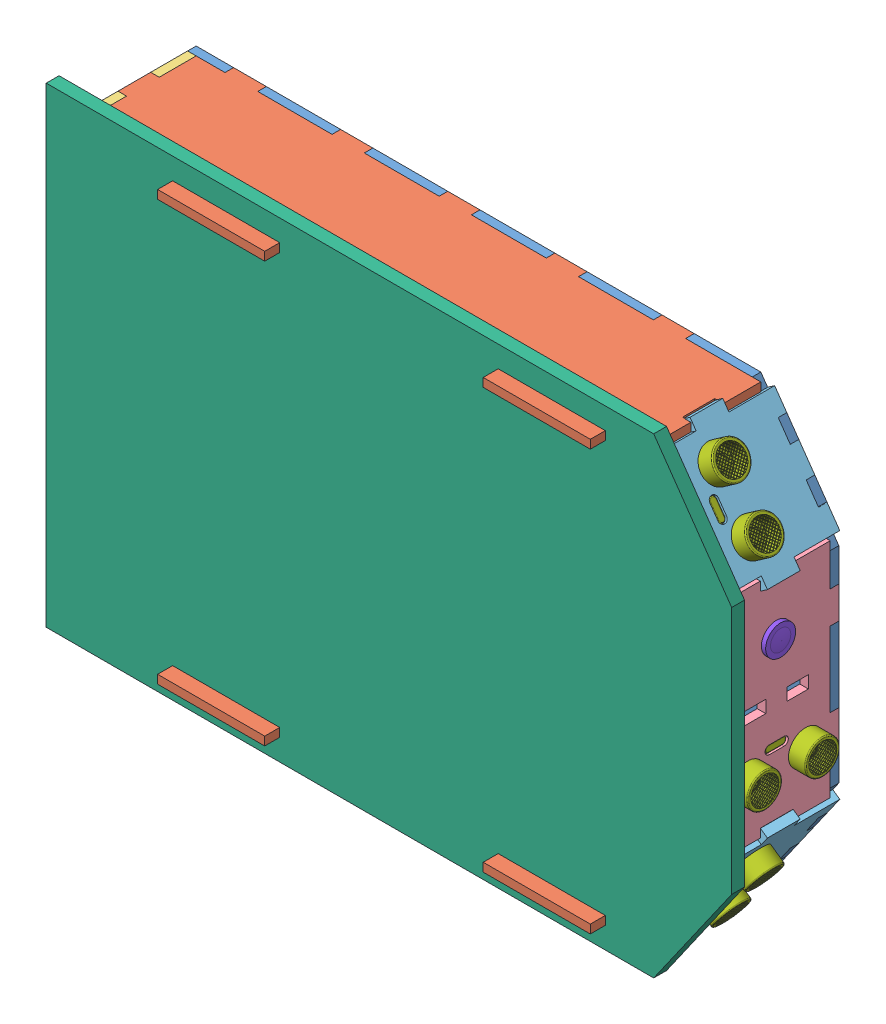
SolidWorks assembly Gehäuse, configuration Standard. Lengths in mm.
Overall size (320 220 121.67).
12 component instances, 8 part files, 34 mates.
Components (placement in the parent):
- Gehäuseunterteil-1: Gehäuseunterteil [Standard] at origin size (300 200 4)
- Gehäuse_seite-1: Gehäuse_seite [Standard] at (0 200 4) x (1 0 0) z (0 -1 0) size (267.59 67 4)
- Gehäuse_seite-2: Gehäuse_seite [Standard] at (0 4 4) x (1 0 0) z (0 -1 0) size (267.59 67 4)
- Gehause_hinten-1: Gehause_hinten [Standard] at (0 0 4) x (0 1 0) z (1 0 0) size (200 54 4)
- Gehause_vorne-2: Gehause_vorne [Standard] at (300 200.05 4) x (0 -1 0) z (-1 0 0) size (103.9 54 4)
- Seitenteil_Gehäuse-1: Seitenteil_Gehäuse [Standard] at (267.1933 201.8266 0) x (0.573576 -0.819152 0) z (-0.819152 -0.573576 0) size (63 54 4)
- Seitenteil_Gehäuse-2: Seitenteil_Gehäuse [Standard] at (263.9167 0.4677 0) x (0.573576 0.819152 0) z (0.819152 -0.573576 0) size (63 54 4)
- Deckel-1: Deckel [Standard] at (310 210 54) x (-1 0 0) z (0 0 1) size (320 220 6)
- Ultrasonic HCSR04-1: Ultrasonic HCSR04 [Default] at (252.5647 213.1295 111.6627) x (-0.573576 0.819152 0) z (0.819152 0.573576 0) size (45 24.45 19.22)
- Ultrasonic HCSR04-2: Ultrasonic HCSR04 [Default] at (308.9465 67.3922 111.6627) x (0.573576 0.819152 0) z (0.819152 -0.573576 0) size (45 24.45 19.22)
- Ultrasonic HCSR04-3: Ultrasonic HCSR04 [Default] at (294.5 151.8572 -20.1494) x (0 0 -1) z (1 0 0) size (45 24.45 19.22)
- CAMERA PI COM LENTE-1: CAMERA PI COM LENTE [Valor predeterminado] at (284 125.3845 32.3972) x (0 -1 0) z (1 0 0) size (25 24 20.55)
Mates (geometry in assembly coordinates):
- Deckungsgleich3: coincident: plane of Gehäuseunterteil-1 through (0 0 0) normal (0 0 -1); plane of Gehäuse_seite-1 through (17.45 196 0) normal (0 0 -1)
- Deckungsgleich4: coincident: plane of Gehäuseunterteil-1 through (0 0 0) normal (0 0 -1); plane of Gehäuse_seite-2 through (167.45 0 0) normal (0 0 -1)
- Deckungsgleich7: coincident: plane of Gehäuseunterteil-1 through (4 82.5 -0.001) normal (-1 0 0); plane of Gehause_hinten-1 through (4 0 4) normal (1 0 0)
- Deckungsgleich9: coincident: plane of Gehäuseunterteil-1 through (0 0 0) normal (0 0 -1); plane of Gehause_hinten-1 through (0 182.55 0) normal (0 0 -1)
- Deckungsgleich12: coincident: plane of Gehäuseunterteil-1 through (300 200 4) normal (1 0 0); plane of Gehause_vorne-2 through (300 200.05 4) normal (1 0 0)
- Deckungsgleich17: coincident: plane of Gehäuse_seite-1 through (4 200.001 54) normal (-1 0 0); plane of Gehause_hinten-1 through (4 0 4) normal (1 0 0)
- Deckungsgleich18: coincident: plane of Gehäuseunterteil-1 through (0 200 4) normal (0 1 0); plane of Gehäuse_seite-1 through (0 200 4) normal (0 1 0)
- Deckungsgleich19: coincident: plane of Gehäuseunterteil-1 through (67.5 4 -0.001) normal (0 -1 0); plane of Gehäuse_seite-2 through (0 4 4) normal (0 1 0)
- Deckungsgleich20: coincident: plane of Gehäuse_seite-2 through (4 4.001 21.05) normal (-1 0 0); plane of Gehause_hinten-1 through (4 0 4) normal (1 0 0)
- Deckungsgleich21: coincident: plane of Gehäuse_seite-1 through (0 196 4) normal (0 -1 0); plane of Gehause_hinten-1 through (-0.001 196 36.5) normal (0 1 0)
- Deckungsgleich22: coincident: plane of Gehäuseunterteil-1 through (300 200 4) normal (1 0 0); plane of Gehause_vorne-2 through (300 200.05 4) normal (1 0 0)
- Deckungsgleich23: coincident: plane of Gehäuseunterteil-1 through (0 0 0) normal (0 0 -1); plane of Gehause_vorne-2 through (300 67.5 0) normal (0 0 -1)
- Deckungsgleich24: coincident: plane of Gehäuseunterteil-1 through (300 67.5 -0.001) normal (0 1 0); plane of Gehause_vorne-2 through (300 67.5 4) normal (0 -1 0)
- Deckungsgleich26: coincident: plane of Gehäuseunterteil-1 through (291.2586 160.484 -0.001) normal (0.819152 0.573576 0); plane of Seitenteil_Gehäuse-1 through (263.9167 199.5323 0) normal (-0.819152 -0.573576 0)
- Deckungsgleich30: coincident: line of Gehäuse_seite-1 through (267.5892 196 54) axis (0 0 -1); plane of Seitenteil_Gehäuse-1 through (270.062 197.7315 54) normal (-0.573576 0.819152 0)
- Deckungsgleich31: coincident: plane of Gehäuseunterteil-1 through (0 0 4) normal (0 0 1); plane of Seitenteil_Gehäuse-1 through (275.7514 189.6061 4) normal (0 0 -1)
- Deckungsgleich32: coincident: plane of Gehäuseunterteil-1 through (278.0664 20.6755 -0.001) normal (0.819152 -0.573576 0); plane of Seitenteil_Gehäuse-2 through (263.9167 0.4677 0) normal (-0.819152 0.573576 0)
- Deckungsgleich33: coincident: plane of Gehäuseunterteil-1 through (0 0 0) normal (0 0 -1); plane of Seitenteil_Gehäuse-2 through (267.1933 -1.8266 0) normal (0 0 -1)
- Deckungsgleich36: coincident: line of Gehäuse_seite-2 through (267.5892 4 36.5) axis (0 0 1); plane of Seitenteil_Gehäuse-2 through (266.7837 4.564 54) normal (-0.573576 -0.819152 0)
- Deckungsgleich63: coincident: plane of Gehäuseunterteil-1 through (150 0 0) normal (-1 0 0); plane of Deckel-1 through (150 210 54) normal (-1 0 0)
- Deckungsgleich64: coincident: plane of Gehäuse_seite-1 through (0 196 54) normal (0 0 1); plane of Deckel-1 through (310 210 54) normal (0 0 -1)
- Deckungsgleich65: coincident: plane of Gehäuseunterteil-1 through (0 100 0) normal (0 1 0); plane of Deckel-1 through (310 100 54) normal (0 -1 0)
- Deckungsgleich66: coincident: plane of Seitenteil_Gehäuse-1 through (263.9167 199.5323 0) normal (-0.819152 -0.573576 0); plane of Ultrasonic HCSR04-1 through (253.7934 213.9899 111.6627) normal (0.819152 0.573576 0)
- Parallel4: parallel: plane of Seitenteil_Gehäuse-1 through (263.9167 199.5323 54) normal (0 0 1); plane of Ultrasonic HCSR04-1 through (294.8898 155.2981 44) normal (0 0 1)
- Konzentrisch1: concentric: cylinder of Seitenteil_Gehäuse-1 through (293.005 164.9654 34) axis (-0.819152 -0.573576 0) radius 8; cylinder of Ultrasonic HCSR04-1 through (299.5574 169.5534 34) axis (-0.819152 -0.573576 0) radius 8
- Konzentrisch2: concentric: cylinder of Seitenteil_Gehäuse-2 through (289.7268 37.3301 34) axis (0.819152 -0.573576 0) radius 8; cylinder of Ultrasonic HCSR04-2 through (299.5574 30.4466 34) axis (-0.819152 0.573576 0) radius 8
- Deckungsgleich68: coincident: plane of Seitenteil_Gehäuse-2 through (263.9167 0.4677 0) normal (-0.819152 0.573576 0); plane of Ultrasonic HCSR04-2 through (310.1753 66.5318 111.6627) normal (0.819152 -0.573576 0)
- Konzentrisch3: concentric: cylinder of Seitenteil_Gehäuse-2 through (274.2402 15.213 34) axis (0.819152 -0.573576 0) radius 8; cylinder of Ultrasonic HCSR04-2 through (284.0709 8.3295 34) axis (-0.819152 0.573576 0) radius 8
- Konzentrisch4: concentric: cylinder of Gehause_vorne-2 through (300.001 74.1945 15.5) axis (-1 0 0) radius 8; cylinder of Ultrasonic HCSR04-3 through (308 74.1945 15.5) axis (-1 0 0) radius 8
- Konzentrisch5: concentric: cylinder of Gehause_vorne-2 through (300.001 74.1945 42.5) axis (-1 0 0) radius 8; cylinder of Ultrasonic HCSR04-3 through (308 74.1945 42.5) axis (-1 0 0) radius 8
- Deckungsgleich69: coincident: plane of Gehause_vorne-2 through (296 200.05 4) normal (-1 0 0); plane of Ultrasonic HCSR04-3 through (296 151.8572 -20.1494) normal (1 0 0)
- Parallel5: parallel: cylinder of Gehause_vorne-2 through (300.001 125.2078 29) axis (-1 0 0) radius 7; face of CAMERA PI COM LENTE-1
- Parallel6: parallel: plane of Gehäuseunterteil-1 through (0 0 4) normal (0 0 1); plane of CAMERA PI COM LENTE-1 through (283 137.8845 44.3972) normal (0 0 1)
- Abstand1: distance = 2 mm: plane of CAMERA PI COM LENTE-1 through (302 125.3845 29.1472) normal (1 0 0); plane of Gehause_vorne-2 through (300 200.05 4) normal (1 0 0)
